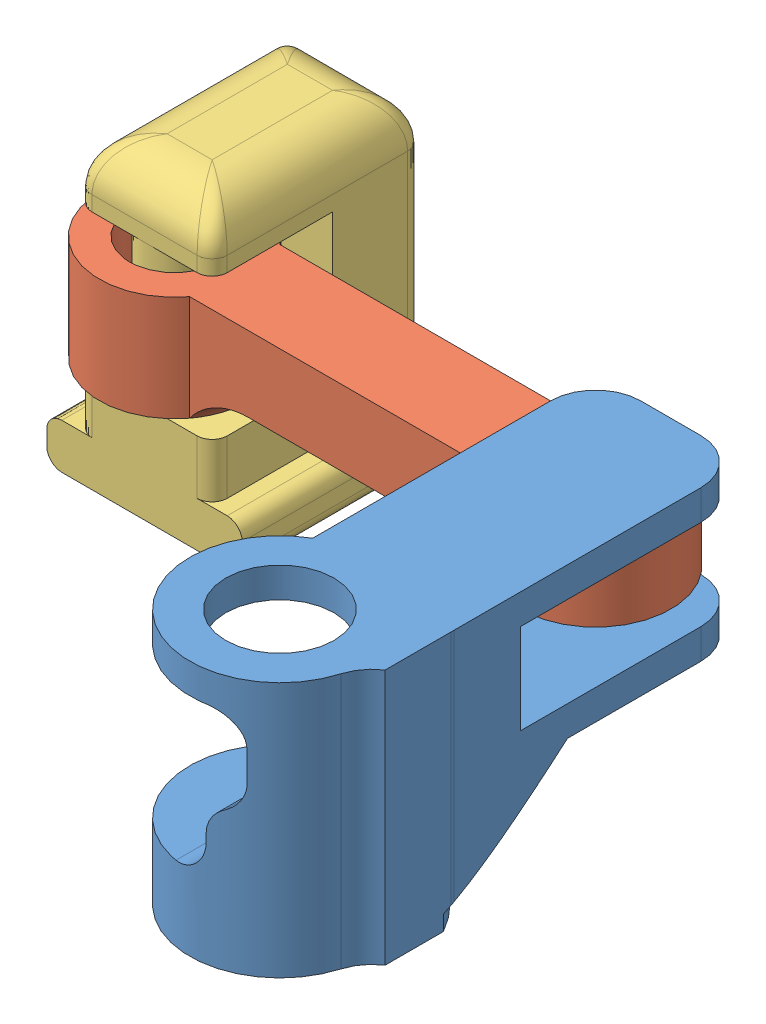
SolidWorks assembly Assembly_Arm_12mm_14mm, configuration Default. Lengths in mm.
Overall size (20.76 10 19.5).
3 component instances, 3 part files, 3 mates.
Components (placement in the parent):
- Slider_Gear_Arm_12mm-1: Slider_Gear_Arm_12mm [Default] at (-34.5505 5.4901 15.6145) size (6.5 8.5 15)
- Arm-1: Arm [Default] at (-34.5505 9.2401 5.1145) size (19 3.64 5)
- Slider-1: Slider [Default] at (-48.5505 7.5563 7.1145) x (-1 0 0) z (0 0 1) size (6.5 10 7)
Mates (geometry in assembly coordinates):
- Concentric1: concentric aligned: cylinder of Slider_Gear_Arm_12mm-1 through (-34.5505 8.9901 5.1145) axis (0 1 0) radius 1; cylinder of Arm-1 through (-34.5505 9.2401 5.1145) axis (0 1 0) radius 1.5
- Coincident1: coincident anti-aligned: plane of Slider_Gear_Arm_12mm-1 through (-34.5505 9.9901 15.6145) normal (0 1 0); plane of Arm-1 through (-34.5505 9.9901 5.1145) normal (0 -1 0)
- Concentric2: concentric anti-aligned: cylinder of Arm-1 through (-48.5505 19.2401 5.1145) axis (0 -1 0) radius 1.5; cylinder of Slider-1 through (-48.5505 5.8063 5.1145) axis (0 1 0) radius 1
